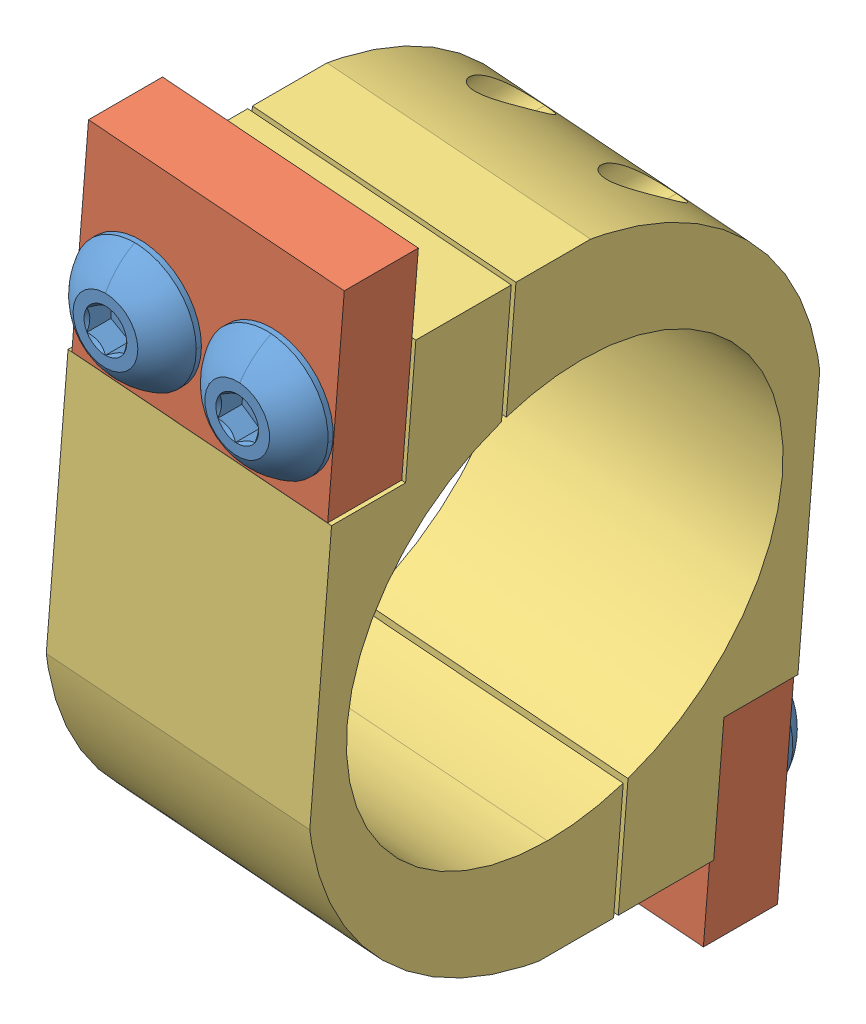
SolidWorks assembly Clamping-Drum-Assembly.STEP, configuration Default. Lengths in mm.
Overall size (21.52 53.54 36.43).
8 component instances, 3 part files, 0 mates.
Components (placement in the parent):
- BHSCS 8-32x0.75in - 91255A197_ALLOY STEEL BUTTON-HEAD SOCKET CAP SCREW_91255A197.STEP-1: BHSCS 8-32x0.75in - 91255A197_ALLOY STEEL BUTTON-HEAD SOCKET CAP SCREW_91255A197.STEP [Default] at origin size (7.92 7.92 21.27)
- V-Spin Tooth R2.STEP-1: V-Spin Tooth R2.STEP [Default] at (1.3141 -37.17 -29.4473) x (0.996867 -0.079097 0) z (0.079097 0.996867 0) size (16.5 4.76 13.5)
- V-Spin Clamp Half R2.STEP-1: V-Spin Clamp Half R2.STEP [Default] at (-5.6201 -17.1089 -18.2098) x (0.996867 -0.079097 0) z (0.079097 0.996867 0) size (17 20.8 42)
- BHSCS 8-32x0.75in - 91255A197_ALLOY STEEL BUTTON-HEAD SOCKET CAP SCREW_91255A197.STEP-2: BHSCS 8-32x0.75in - 91255A197_ALLOY STEEL BUTTON-HEAD SOCKET CAP SCREW_91255A197.STEP [Default] at (-2.7684 -34.89 -36.4196) x (0.710764 0.703431 0) z (0 0 -1) size (7.92 7.92 21.27)
- BHSCS 8-32x0.75in - 91255A197_ALLOY STEEL BUTTON-HEAD SOCKET CAP SCREW_91255A197.STEP-3: BHSCS 8-32x0.75in - 91255A197_ALLOY STEEL BUTTON-HEAD SOCKET CAP SCREW_91255A197.STEP [Default] at (5.705 -35.5623 -36.4196) x (-0.827982 -0.560755 0) z (0 0 -1) size (7.92 7.92 21.27)
- V-Spin Clamp Half R2.STEP-2: V-Spin Clamp Half R2.STEP [Default] at (-5.6201 -17.1089 -18.2098) x (0.996867 -0.079097 0) z (-0.079097 -0.996867 0) size (17 20.8 42)
- V-Spin Tooth R2.STEP-2: V-Spin Tooth R2.STEP [Default] at (4.3909 1.6077 -6.9723) x (0.996867 -0.079097 0) z (-0.079097 -0.996867 0) size (16.5 4.76 13.5)
- BHSCS 8-32x0.75in - 91255A197_ALLOY STEEL BUTTON-HEAD SOCKET CAP SCREW_91255A197.STEP-4: BHSCS 8-32x0.75in - 91255A197_ALLOY STEEL BUTTON-HEAD SOCKET CAP SCREW_91255A197.STEP [Default] at (8.4734 -0.6723 0) x (0.996867 -0.079097 0) z (0 0 1) size (7.92 7.92 21.27)
